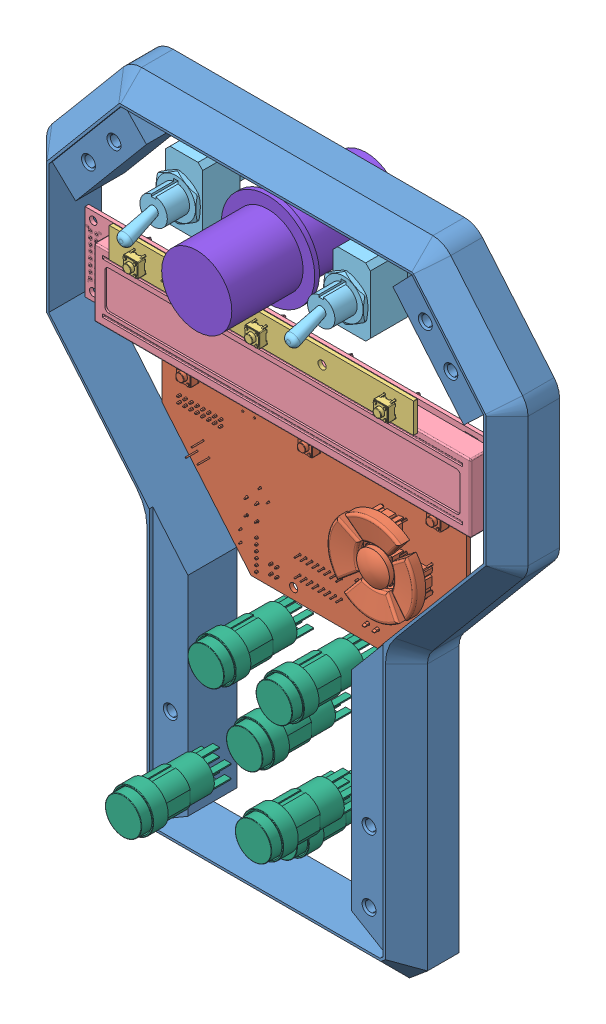
SolidWorks assembly Montagem005, configuration Valor predeterminado. Lengths in mm.
Overall size (206 280 84.5).
14 component instances, 8 part files, 4 mates.
Components (placement in the parent):
- 5 - TEC02 - Moldura segurança -1: 5 - TEC02 - Moldura segurança  [Valor predeterminado] at (14.6268 -144.0158 -11.25) size (206 280 22.5)
- PCB_IHM-1: PCB_IHM [Valor predeterminado] at (-11.7088 -40.0882 -8.6761) size (130.25 70.25 27.35)
- PCB_IHM_Teclas_Superiores-1: PCB_IHM_Teclas_Superiores [Valor predeterminado] at (-48.3177 70.5295 15.34) size (130.25 12.75 19.2)
- LCD Display 4002-1: LCD Display 4002 [Valor predeterminado] at (14.8769 50.8587 -6.5614) size (182 33.5 13.65)
- BCV3 112 103 - Controle chave geral-1: BCV3 112 103 - Controle chave geral [Default] at (-21.7613 105.6393 2) size (17 29 51.5)
- BCV3 112 103 - Controle chave geral-2: BCV3 112 103 - Controle chave geral [Default] at (52.4197 106.7327 4.4985) size (17 29 51.5)
- BCV3 112 102 - Controle botão-2: BCV3 112 102 - Controle botão [Valor predeterminado] at (28.8171 -51.679 11.7) x (1 0 0) z (0 -1 0) size (17.7 39.7 17.7)
- BCV3 112 102 - Controle botão-3: BCV3 112 102 - Controle botão [Valor predeterminado] at (16.1487 -75.1329 11.7) x (1 0 0) z (0 -1 0) size (17.7 39.7 17.7)
- BCV3 112 102 - Controle botão-4: BCV3 112 102 - Controle botão [Valor predeterminado] at (35.5939 -91.6907 27.35) x (1 0 0) z (0 -1 0) size (17.7 39.7 17.7)
- BCV3 112 102 - Controle botão-5: BCV3 112 102 - Controle botão [Valor predeterminado] at (-4.3561 -94.7314 43) x (1 0 0) z (0 -1 0) size (17.7 39.7 17.7)
- BCV3 112 102 - Controle botão-6: BCV3 112 102 - Controle botão [Valor predeterminado] at (17.4235 -113.9494 -1.8) x (1 0 0) z (0 -1 0) size (17.7 39.7 17.7)
- BCV3 112 102 - Controle botão-7: BCV3 112 102 - Controle botão [Valor predeterminado] at (-0.3319 -52.6274 11.7) x (1 0 0) z (0 -1 0) size (17.7 39.7 17.7)
- hex nut style 1 gradeab_din-1: hex nut style 1 gradeab_din [Hexagon Nut ISO 4032 - M4 - W - N] at (-62.8707 96.4837 -1.25) x (-1 0 0) z (0 0 1) size (7 8.08 3.2)
- Botão emergencia-1: Botão emergencia [Valor predeterminado] at (15.4178 104.028 -30.75) x (1 0 0) z (0 -1 0) size (40 72.5 40)
Mates (geometry in assembly coordinates):
- Concêntrico2: concentric aligned: cylinder of 5 - TEC02 - Moldura segurança -1 through (-62.8707 96.4837 11.25) axis (0 0 1) radius 2.25; cylinder of hex nut style 1 gradeab_din-1 through (-62.8707 96.4837 -4.45) axis (0 0 1) radius 1.65
- Coincidente5: coincident anti-aligned: plane of 5 - TEC02 - Moldura segurança -1 through (-59.3707 94.463 -1.25) normal (-1 0 0); plane of hex nut style 1 gradeab_din-1 through (-59.3707 94.463 -4.45) normal (1 0 0)
- Coincidente6: coincident anti-aligned: plane of 5 - TEC02 - Moldura segurança -1 through (14.6268 -144.0158 -1.25) normal (0 0 -1); plane of hex nut style 1 gradeab_din-1 through (-55.8707 96.4837 -1.25) normal (0 0 1)
- Coincidente8: coincident aligned: plane of 5 - TEC02 - Moldura segurança -1 through (14.6268 -144.0158 11.25) normal (0 0 1); plane of Botão emergencia-1 through (-4.5822 104.028 11.25) normal (0 0 1)
